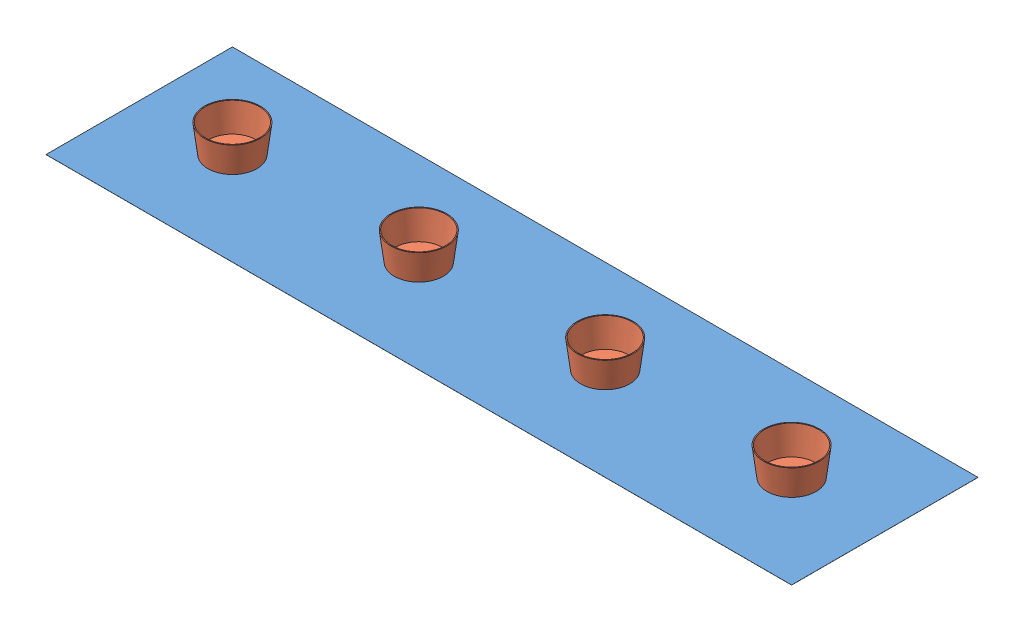
SolidWorks assembly Assem1, configuration Default. Lengths in mm.
Overall size (8000 350 2000).
5 component instances, 2 part files, 8 mates.
Components (placement in the parent):
- mat-1: mat [Default] at origin size (8000 1 2000)
- tub-1: tub [blue] at (-3000 301 0) x (0.96669 0 0.255952) z (-0.255952 0 0.96669) size (600 300 600)
- tub-2: tub [red] at (-1000 301 0) size (600 300 600)
- tub-5: tub [red] at (1000 301 0) size (600 300 600)
- tub-6: tub [red] at (3000 301 0) size (600 300 600)
Mates (geometry in assembly coordinates):
- Coincident4: coincident: point of mat-1; point of tub-1
- Coincident5: coincident anti-aligned: plane of mat-1 through (0 1 0) normal (0 1 0); plane of tub-1 through (-3000 1 0) normal (0 -1 0)
- Coincident6: coincident: point of mat-1; point of tub-2
- Coincident7: coincident anti-aligned: plane of mat-1 through (0 1 0) normal (0 1 0); plane of tub-2 through (-1000 1 0) normal (0 -1 0)
- Coincident8: coincident: point of mat-1; point of tub-5
- Coincident9: coincident anti-aligned: plane of mat-1 through (0 1 0) normal (0 1 0); plane of tub-5 through (1000 1 0) normal (0 -1 0)
- Coincident10: coincident: point of mat-1; point of tub-6
- Coincident11: coincident anti-aligned: plane of mat-1 through (0 1 0) normal (0 1 0); plane of tub-6 through (3000 1 0) normal (0 -1 0)
